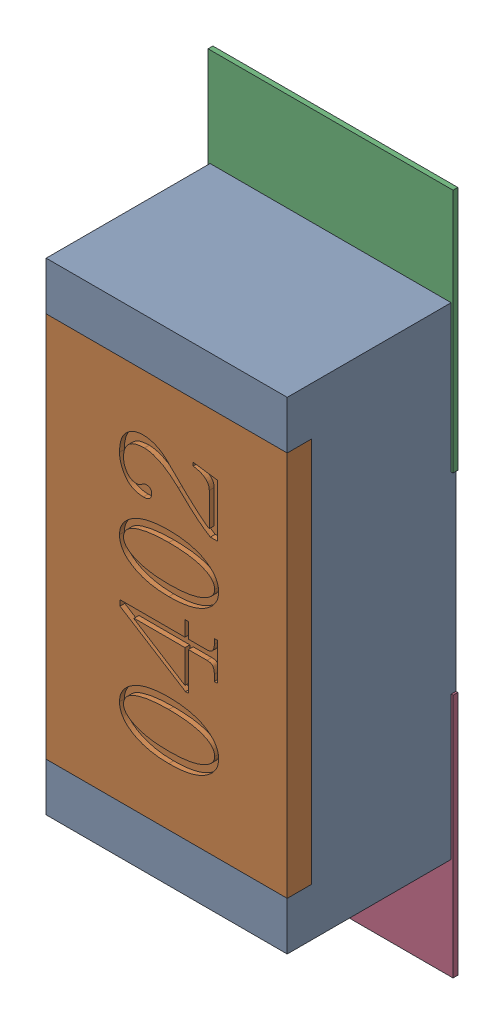
SolidWorks assembly R89, configuration Défaut. Lengths in mm.
Overall size (0.51 1.42 0.35).
5 component instances, 2 part files, 0 mates.
Components (placement in the parent):
- R0402-1: R0402 [Défaut] at (50.5247 -22.0504 0) x (0 1 0) z (0 0 1) size (1 0.5 0.35)
- 6504207776-1: 6504207776 [Défaut] at (50.5245 -21.6004 0) size (0.51 0.51 0.01)
  - Extruded-1: Extruded [Défaut] at origin size (0.51 0.51 0.01)
- 6504207776-2: 6504207776 [Défaut] at (50.5245 -22.5075 0) size (0.51 0.51 0.01)
  - Extruded-1: Extruded [Défaut] at origin size (0.51 0.51 0.01)
